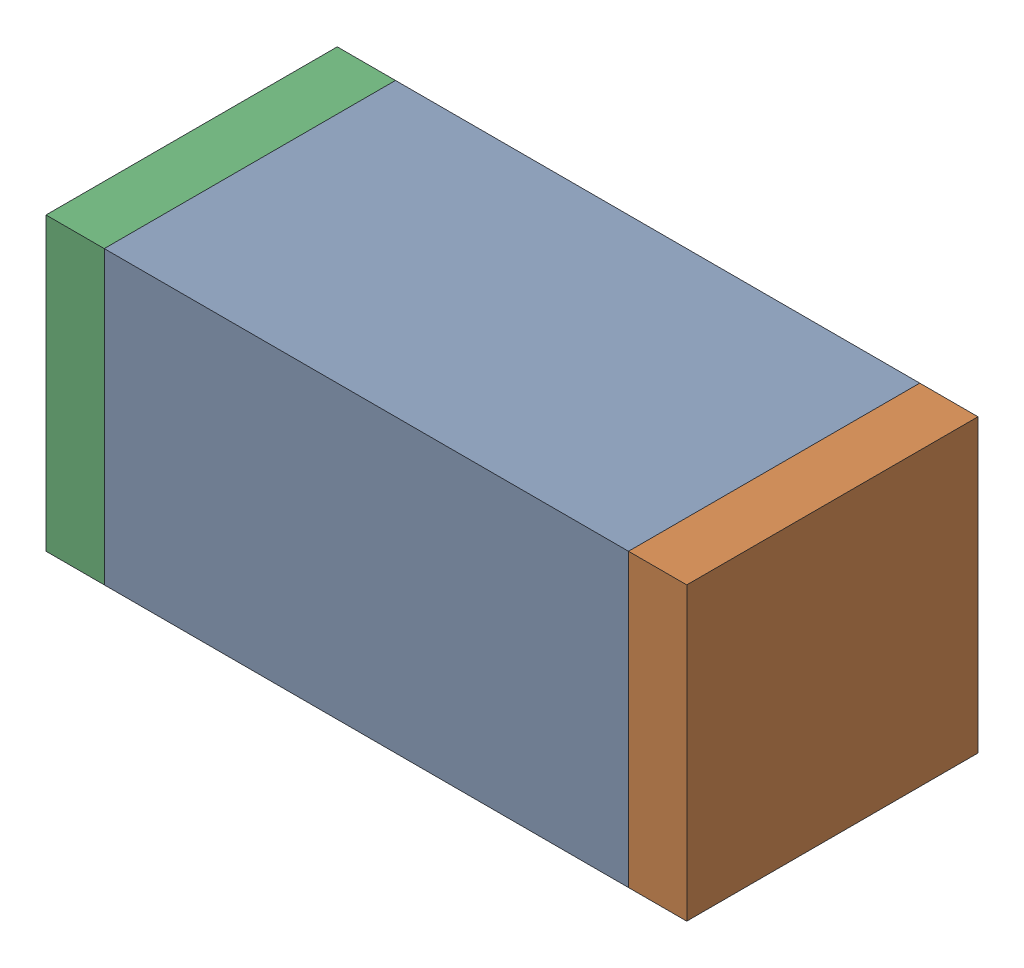
SolidWorks assembly C104, configuration Default. Lengths in mm.
Overall size (1.1 0.5 0.5).
6 component instances, 2 part files, 0 mates.
Components (placement in the parent):
- 836749680-1: 836749680 [Default] at (128.15 71.1 0) size (0.9 0.5 0.5)
  - Extruded_4-1: Extruded_4 [Default] at origin size (0.9 0.5 0.5)
- 810156080-1: 810156080 [Default] at (128.65 71.1 0) size (0.1 0.5 0.5)
  - Extruded_5-1: Extruded_5 [Default] at origin size (0.1 0.5 0.5)
- 810156080-2: 810156080 [Default] at (127.65 71.1 0) size (0.1 0.5 0.5)
  - Extruded_5-1: Extruded_5 [Default] at origin size (0.1 0.5 0.5)
